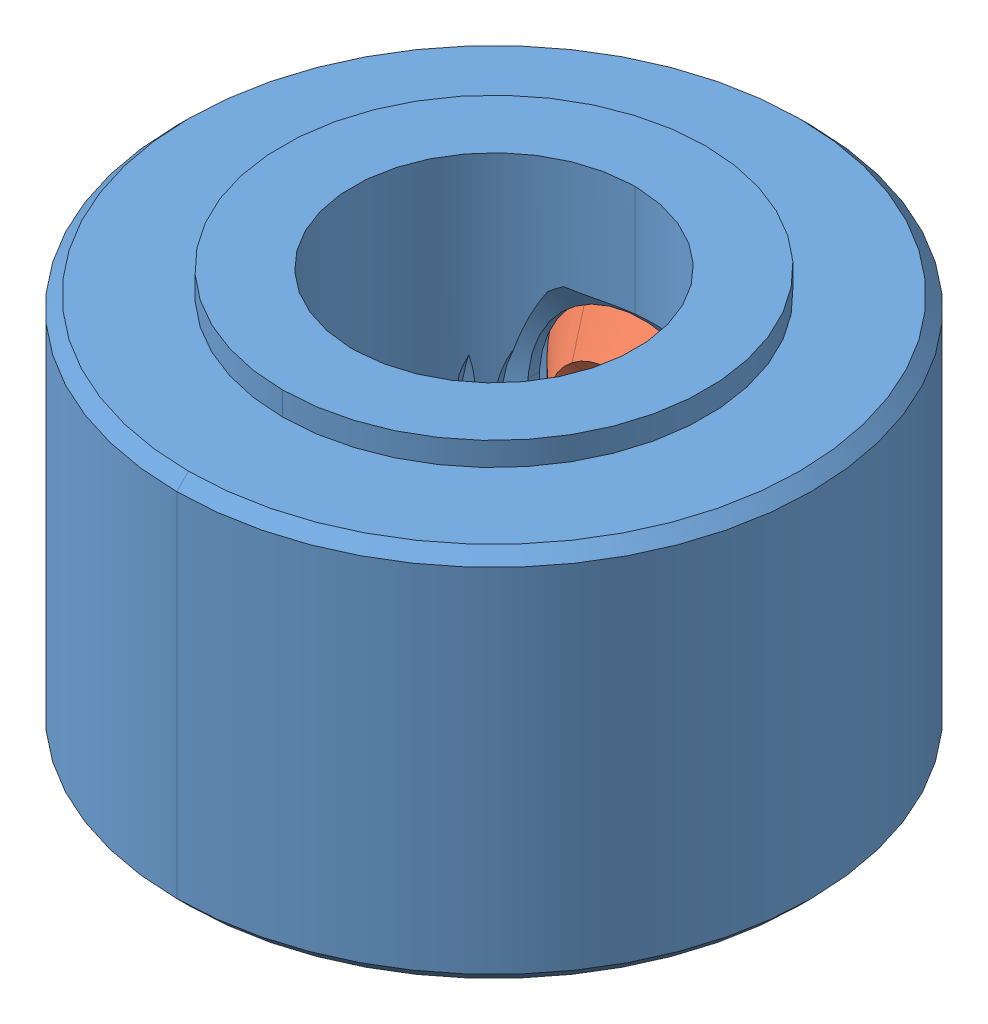
SolidWorks assembly Steel Set-Screw Collar 2920-0001-0006, configuration Default. Lengths in mm.
Overall size (13.5 8.5 13.5).
2 component instances, 2 part files, 0 mates.
Components (placement in the parent):
- 2920-0001-0006.STEP-1: 2920-0001-0006.STEP [Default] at (-59.2617 9.4299 24.6952) size (13.5 8.5 13.5)
- 2806-0005-0004_91390A117.STEP-1: 2806-0005-0004_91390A117.STEP [Default] at (-59.2617 9.4299 19.7837) x (-0.790503 -0.612458 0) z (0 0 -1) size (5.01 5.01 4.01)
